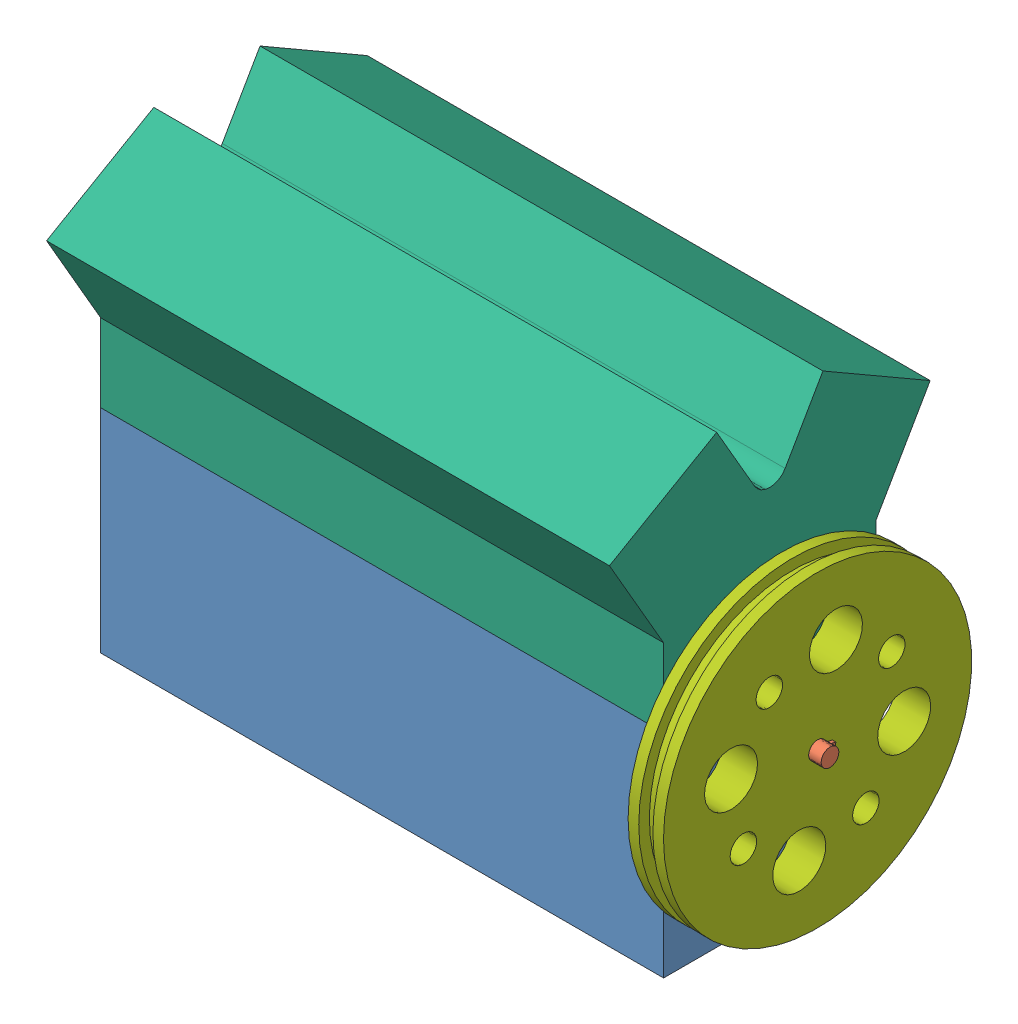
SolidWorks assembly Assem6, configuration Default. Lengths in mm.
Overall size (490.22 330.44 262.15).
28 component instances, 7 part files, 22 mates.
Components (placement in the parent):
- engine base-1: engine base [Default] at (-32.144 103.7633 375.5019) size (403.86 215.9 152.4)
- Crank Shaft-1: Crank Shaft [Default] at (338.696 224.4133 299.3019) x (0 -0.978311 0.207143) z (1 0 0) size (76.2 76.2 490.22)
- Piston.Pin.ConnectingRod-1: Piston.Pin.ConnectingRod [Default] at (205.9145 298.4807 301.2138) x (0 -0.5 -0.866025) z (1 0 0) size (82.43 133.02 44.7) (flexible)
  - Main Piston Part-1: Main Piston Part [Default] at (16.44 4.5855 46.4214) size (44.7 59.44 44.7)
  - Piston-1: Piston [Default] at (16.44 35.0655 25.4664) x (0.889624 0.456694 0) z (0 0 1) size (12.7 12.7 41.91)
  - connecting rod-1: connecting rod [Default] at (62.8401 -55.3203 38.5569) x (0.889624 0.456694 0) z (0 0 1) size (20.32 121.92 12.7)
- Engine Head-1: Engine Head [Default] at (-32.144 256.1633 299.3019) x (0 0 -1) z (1 0 0) size (230.12 167.62 403.86)
- Piston.Pin.ConnectingRod-2: Piston.Pin.ConnectingRod [Default] at (38.2745 268.413 317.997) x (0 0.5 -0.866025) z (1 0 0) size (82.43 133.02 44.7) (flexible)
  - Main Piston Part-1: Main Piston Part [Default] at (16.44 4.5855 46.4214) size (44.7 59.44 44.7)
  - Piston-1: Piston [Default] at (16.44 35.0655 25.4664) x (0.889624 -0.456694 0) z (0 0 1) size (12.7 12.7 41.91)
  - connecting rod-1: connecting rod [Default] at (-29.9601 -55.3203 38.5569) x (0.889624 -0.456694 0) z (0 0 1) size (20.32 121.92 12.7)
- Piston.Pin.ConnectingRod-3: Piston.Pin.ConnectingRod [Default] at (94.1545 316.0366 291.0779) x (0 -0.5 -0.866025) z (1 0 0) size (44.7 140.99 44.7) (flexible)
  - Main Piston Part-1: Main Piston Part [Default] at (16.44 4.5855 46.4214) size (44.7 59.44 44.7)
  - Piston-1: Piston [Default] at (16.44 35.0655 25.4664) x (0.999453 0.033073 0) z (0 0 1) size (12.7 12.7 41.91)
  - connecting rod-1: connecting rod [Default] at (19.8002 -66.479 38.5569) x (0.999453 0.033073 0) z (0 0 1) size (20.32 121.92 12.7)
- Piston.Pin.ConnectingRod-4: Piston.Pin.ConnectingRod [Default] at (-17.6055 278.62 312.6804) x (0 -0.5 -0.866025) z (1 0 0) size (51.06 140.84 44.7) (flexible)
  - Main Piston Part-1: Main Piston Part [Default] at (16.44 4.5855 46.4214) size (44.7 59.44 44.7)
  - Piston-1: Piston [Default] at (16.44 35.0655 25.4664) x (0.985922 0.167205 0) z (0 0 1) size (12.7 12.7 41.91)
  - connecting rod-1: connecting rod [Default] at (33.428 -65.1042 38.5569) x (0.985922 0.167205 0) z (0 0 1) size (20.32 121.92 12.7)
- Piston.Pin.ConnectingRod-5: Piston.Pin.ConnectingRod [Default] at (150.0345 305.2199 339.2475) x (0 0.5 -0.866025) z (1 0 0) size (51.06 140.84 44.7) (flexible)
  - Main Piston Part-1: Main Piston Part [Default] at (16.44 4.5855 46.4214) size (44.7 59.44 44.7)
  - Piston-1: Piston [Default] at (16.44 35.0655 25.4664) x (0.985922 -0.167205 0) z (0 0 1) size (12.7 12.7 41.91)
  - connecting rod-1: connecting rod [Default] at (-0.548 -65.1042 38.5569) x (0.985922 -0.167205 0) z (0 0 1) size (20.32 121.92 12.7)
- Piston.Pin.ConnectingRod-6: Piston.Pin.ConnectingRod [Default] at (261.7945 270.1845 319.0197) x (0 0.5 -0.866025) z (1 0 0) size (44.7 140.99 44.7) (flexible)
  - Main Piston Part-1: Main Piston Part [Default] at (16.44 4.5855 46.4214) size (44.7 59.44 44.7)
  - Piston-1: Piston [Default] at (16.44 35.0655 25.4664) x (0.999453 -0.033073 0) z (0 0 1) size (12.7 12.7 41.91)
  - connecting rod-1: connecting rod [Default] at (13.0798 -66.479 38.5569) x (0.999453 -0.033073 0) z (0 0 1) size (20.32 121.92 12.7)
- fly wheel-1: fly wheel [Default] at (380.606 224.4133 299.3019) x (0 -0.978311 0.207143) z (1 0 0) size (221.14 221.14 25.4)
Mates (geometry in assembly coordinates):
- Concentric1: concentric anti-aligned: cylinder of engine base-1 through (31.356 224.4133 299.3019) axis (-1 0 0) radius 6.985; cylinder of Crank Shaft-1 through (-75.324 224.4133 299.3019) axis (1 0 0) radius 6.985
- Width1: width aligned: plane of engine base-1 through (371.716 256.1633 375.5019) normal (1 0 0); plane of engine base-1 through (-32.144 256.1633 375.5019) normal (-1 0 0); plane of Crank Shaft-1 through (338.696 224.4133 299.3019) normal (1 0 0); plane of Crank Shaft-1 through (0.876 224.4133 299.3019) normal (-1 0 0)
- Concentric3: concentric anti-aligned: cylinder of Crank Shaft-1 through (-499661.304 219.1519 274.4528) axis (1 0 0) radius 6.35; cylinder of Piston.Pin.ConnectingRod-1/connecting rod-1 through (257.1714 219.1519 274.4528) axis (-1 0 0) radius 6.477
- Concentric4: concentric anti-aligned: cylinder of Crank Shaft-1 through (-499661.304 219.1519 274.4528) axis (1 0 0) radius 6.35; cylinder of Piston.Pin.ConnectingRod-6/connecting rod-1 through (313.0514 219.1519 274.4528) axis (-1 0 0) radius 6.477
- Concentric5: concentric anti-aligned: cylinder of Crank Shaft-1 through (-499775.604 248.564 307.1699) axis (1 0 0) radius 6.35; cylinder of Piston.Pin.ConnectingRod-5/connecting rod-1 through (201.2914 248.564 307.1699) axis (-1 0 0) radius 6.477
- Concentric6: concentric anti-aligned: cylinder of Crank Shaft-1 through (-499775.604 248.564 307.1699) axis (1 0 0) radius 6.35; cylinder of Piston.Pin.ConnectingRod-3/connecting rod-1 through (145.4114 248.564 307.1699) axis (-1 0 0) radius 6.477
- Concentric7: concentric anti-aligned: cylinder of Crank Shaft-1 through (-499775.604 248.564 307.1699) axis (1 0 0) radius 6.35; cylinder of Piston.Pin.ConnectingRod-3/connecting rod-1 through (145.4114 248.564 307.1699) axis (-1 0 0) radius 6.477
- Concentric8: concentric anti-aligned: cylinder of Crank Shaft-1 through (-499775.604 248.564 307.1699) axis (1 0 0) radius 6.35; cylinder of Piston.Pin.ConnectingRod-3/connecting rod-1 through (145.4114 248.564 307.1699) axis (-1 0 0) radius 6.477
- Concentric9: concentric anti-aligned: cylinder of Crank Shaft-1 through (-499889.904 205.5241 316.283) axis (1 0 0) radius 6.35; cylinder of Piston.Pin.ConnectingRod-2/connecting rod-1 through (89.5314 205.5241 316.283) axis (-1 0 0) radius 6.477
- Concentric10: concentric anti-aligned: cylinder of Crank Shaft-1 through (-499889.904 205.5241 316.283) axis (1 0 0) radius 6.35; cylinder of Piston.Pin.ConnectingRod-4/connecting rod-1 through (33.6514 205.5241 316.283) axis (-1 0 0) radius 6.477
- Concentric23: concentric aligned: cylinder of engine base-1 through (-19.444 319.6633 362.8019) axis (0 -1 0) radius 5.715; cylinder of Engine Head-1 through (-19.444 332.3633 362.8019) axis (0 -1 0) radius 6.35
- Concentric24: concentric aligned: cylinder of engine base-1 through (359.016 319.6633 235.8019) axis (0 -1 0) radius 5.715; cylinder of Engine Head-1 through (359.016 332.3633 235.8019) axis (0 -1 0) radius 6.35
- Coincident10: coincident anti-aligned: plane of engine base-1 through (-32.144 256.1633 375.5019) normal (0 1 0); plane of Engine Head-1 through (371.716 256.1633 299.3019) normal (0 -1 0)
- Concentric25: concentric anti-aligned: cylinder of Engine Head-1 through (28.816 35.3153 434.1691) axis (0 0.866025 -0.5) radius 22.86; cylinder of Piston.Pin.ConnectingRod-4/Main Piston Part-1 through (28.816 274.3711 296.1502) axis (0 -0.866025 0.5) radius 22.352
- Concentric29: concentric anti-aligned: cylinder of Piston.Pin.ConnectingRod-1/Main Piston Part-1 through (252.336 294.2319 284.6836) axis (0 -0.866025 0.5) radius 22.352; cylinder of Engine Head-1 through (252.336 35.3153 434.1691) axis (0 0.866025 -0.5) radius 22.86
- Concentric30: concentric anti-aligned: cylinder of Engine Head-1 through (308.216 35.3153 164.4347) axis (0 0.866025 0.5) radius 22.86; cylinder of Piston.Pin.ConnectingRod-6/Main Piston Part-1 through (308.216 282.3756 307.075) axis (0 -0.866025 -0.5) radius 22.352
- Concentric31: concentric anti-aligned: cylinder of Engine Head-1 through (196.456 35.3153 164.4347) axis (0 0.866025 0.5) radius 22.86; cylinder of Piston.Pin.ConnectingRod-5/Main Piston Part-1 through (196.456 317.411 327.3027) axis (0 -0.866025 -0.5) radius 22.352
- Concentric32: concentric anti-aligned: cylinder of Engine Head-1 through (140.576 35.3153 434.1691) axis (0 0.866025 -0.5) radius 22.86; cylinder of Piston.Pin.ConnectingRod-3/Main Piston Part-1 through (140.576 311.7877 274.5477) axis (0 -0.866025 0.5) radius 22.352
- Concentric33: concentric anti-aligned: cylinder of Engine Head-1 through (84.696 35.3153 164.4347) axis (0 0.866025 0.5) radius 22.86; cylinder of Piston.Pin.ConnectingRod-2/Main Piston Part-1 through (84.696 280.6041 306.0522) axis (0 -0.866025 -0.5) radius 22.352
- Concentric34: concentric anti-aligned: cylinder of Crank Shaft-1 through (414.896 224.4133 299.3019) axis (-1 0 0) radius 6.35; cylinder of fly wheel-1 through (271.894 224.4133 299.3019) axis (1 0 0) radius 6.427
- Width2: width aligned: plane of Crank Shaft-1 through (414.896 224.4133 299.3019) normal (1 0 0); plane of engine base-1 through (371.716 256.1633 375.5019) normal (1 0 0); plane of fly wheel-1 through (406.006 224.4133 299.3019) normal (1 0 0); plane of fly wheel-1 through (380.606 224.4133 299.3019) normal (-1 0 0)
- Coincident19: coincident anti-aligned: plane of Crank Shaft-1 through (338.696 222.3088 289.3623) normal (0 -0.207143 -0.978311); plane of fly wheel-1 through (271.894 225.4149 288.7046) normal (0 0.207143 0.978311)
